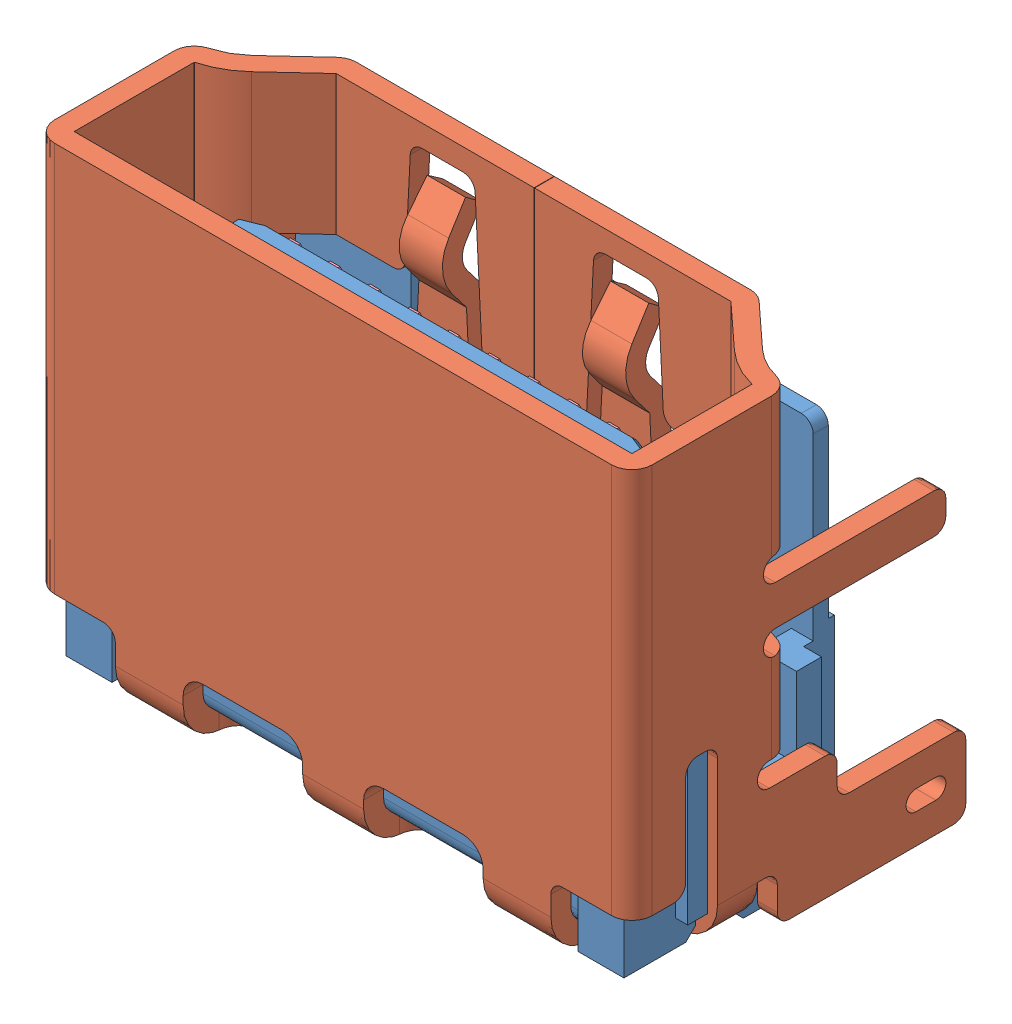
SolidWorks assembly Download_STP_685119134923 (rev1)(3), configuration Défaut. Lengths in mm.
Overall size (15 12.15 8.38).
21 component instances, 4 part files, 0 mates.
Components (placement in the parent):
- 685119134923_Housing-1: 685119134923_Housing [Défaut] at origin size (14.6 10.05 5.78)
- 685119134923_Shielding-1: 685119134923_Shielding [Défaut] at (0.05 3 0.0261) x (-1 0 0) z (0 0 1) size (15 11.6 8.38)
- 685119134923_Pin1-1: 685119134923_Pin1 [Défaut] at (-4.5 2.78 -0.215) x (0 1 0) z (0 0 1) size (9.7 0.45 3.93)
- 685119134923_Pin1-2: 685119134923_Pin1 [Défaut] at (-3.5 2.78 -0.215) x (0 1 0) z (0 0 1) size (9.7 0.45 3.93)
- 685119134923_Pin1-3: 685119134923_Pin1 [Défaut] at (-2.5 2.78 -0.215) x (0 1 0) z (0 0 1) size (9.7 0.45 3.93)
- 685119134923_Pin1-4: 685119134923_Pin1 [Défaut] at (-1.5 2.78 -0.215) x (0 1 0) z (0 0 1) size (9.7 0.45 3.93)
- 685119134923_Pin1-5: 685119134923_Pin1 [Défaut] at (-0.5 2.78 -0.215) x (0 1 0) z (0 0 1) size (9.7 0.45 3.93)
- 685119134923_Pin1-6: 685119134923_Pin1 [Défaut] at (0.5 2.78 -0.215) x (0 1 0) z (0 0 1) size (9.7 0.45 3.93)
- 685119134923_Pin1-7: 685119134923_Pin1 [Défaut] at (1.5 2.78 -0.215) x (0 1 0) z (0 0 1) size (9.7 0.45 3.93)
- 685119134923_Pin1-8: 685119134923_Pin1 [Défaut] at (2.5 2.78 -0.215) x (0 1 0) z (0 0 1) size (9.7 0.45 3.93)
- 685119134923_Pin1-9: 685119134923_Pin1 [Défaut] at (3.5 2.78 -0.215) x (0 1 0) z (0 0 1) size (9.7 0.45 3.93)
- 685119134923_Pin1-10: 685119134923_Pin1 [Défaut] at (4.5 2.78 -0.215) x (0 1 0) z (0 0 1) size (9.7 0.45 3.93)
- 685119134923_Pin2-1: 685119134923_Pin2 [Défaut] at (-4 2.78 -0.865) x (0 1 0) z (0 0 1) size (9.7 0.45 3.28)
- 685119134923_Pin2-2: 685119134923_Pin2 [Défaut] at (-3 2.78 -0.865) x (0 1 0) z (0 0 1) size (9.7 0.45 3.28)
- 685119134923_Pin2-3: 685119134923_Pin2 [Défaut] at (-2 2.78 -0.865) x (0 1 0) z (0 0 1) size (9.7 0.45 3.28)
- 685119134923_Pin2-4: 685119134923_Pin2 [Défaut] at (-1 2.78 -0.865) x (0 1 0) z (0 0 1) size (9.7 0.45 3.28)
- 685119134923_Pin2-5: 685119134923_Pin2 [Défaut] at (0 2.78 -0.865) x (0 1 0) z (0 0 1) size (9.7 0.45 3.28)
- 685119134923_Pin2-6: 685119134923_Pin2 [Défaut] at (1 2.78 -0.865) x (0 1 0) z (0 0 1) size (9.7 0.45 3.28)
- 685119134923_Pin2-7: 685119134923_Pin2 [Défaut] at (2 2.78 -0.865) x (0 1 0) z (0 0 1) size (9.7 0.45 3.28)
- 685119134923_Pin2-8: 685119134923_Pin2 [Défaut] at (3 2.78 -0.865) x (0 1 0) z (0 0 1) size (9.7 0.45 3.28)
- 685119134923_Pin2-9: 685119134923_Pin2 [Défaut] at (4 2.78 -0.865) x (0 1 0) z (0 0 1) size (9.7 0.45 3.28)
